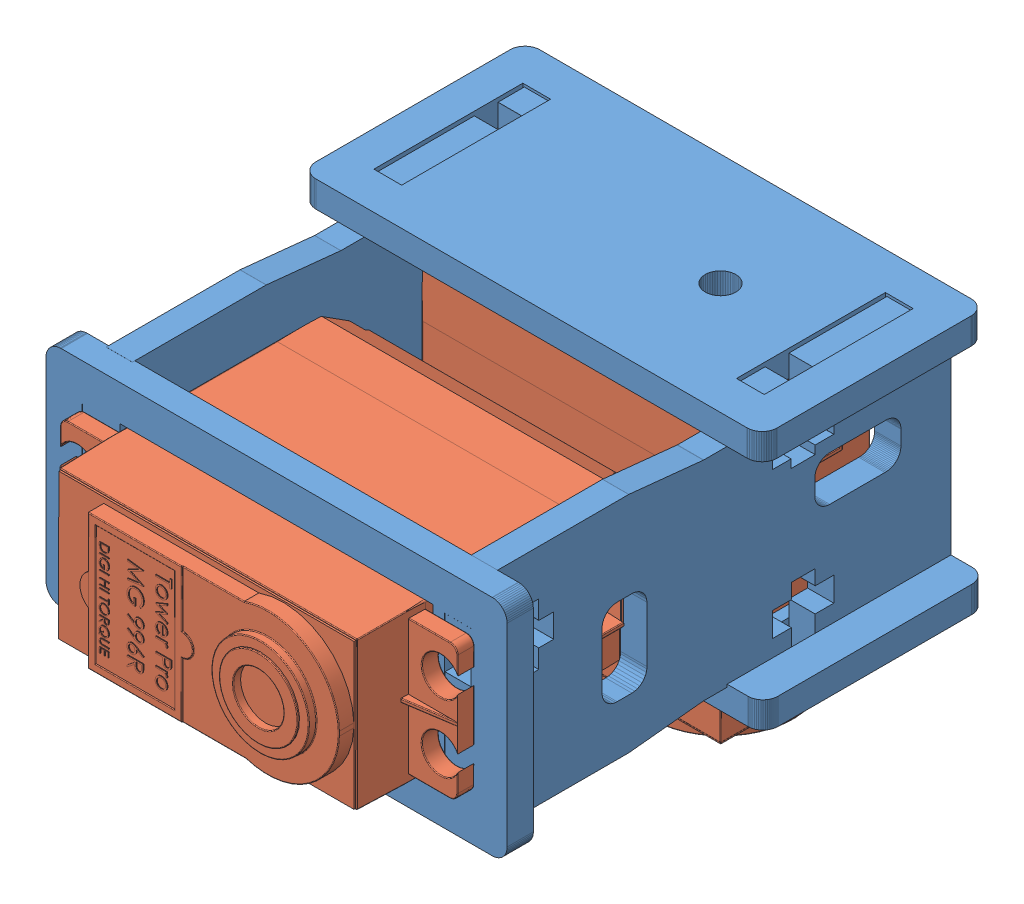
SolidWorks assembly Assem3, configuration Default. Lengths in mm.
Overall size (61.58 46.99 76.54).
5 component instances, 2 part files, 2 mates.
Components (placement in the parent):
- right_upper_arm_100-1: right_upper_arm_100 [Default] at origin size (61.58 34.51 64.01)
- main_assembly-1: main_assembly [Default] at (-3.7391 66.095 29.8837) x (0 -0.000929 -1) z (0 -1 0.000929) size (20 53 41.5)
  - main_body-1: main_body [Default] at (15.1003 34.2066 38.7045) size (20 53 41.5)
- main_assembly-2: main_assembly [Default] at (-3.88 39.6258 5.3585) x (0 -0.999999 0.001256) z (0 0.001256 0.999999) size (20 53 41.5)
  - main_body-1: main_body [Default] at (15.1003 34.2066 38.7045) size (20 53 41.5)
Mates (geometry in assembly coordinates):
- Coincident1: coincident anti-aligned: line of right_upper_arm_100-1 through (51.2889 7.3672 4.838) axis (-1 0 0); line of main_assembly-1/main_body-1 through (10.7174 7.3672 4.838) axis (1 0 0)
- Coincident2: coincident anti-aligned: line of right_upper_arm_100-1 through (9.5826 34.5993 64.0694) axis (1 0 0); line of main_assembly-2/main_body-1 through (50.0765 34.5993 64.0694) axis (-1 0 0)
